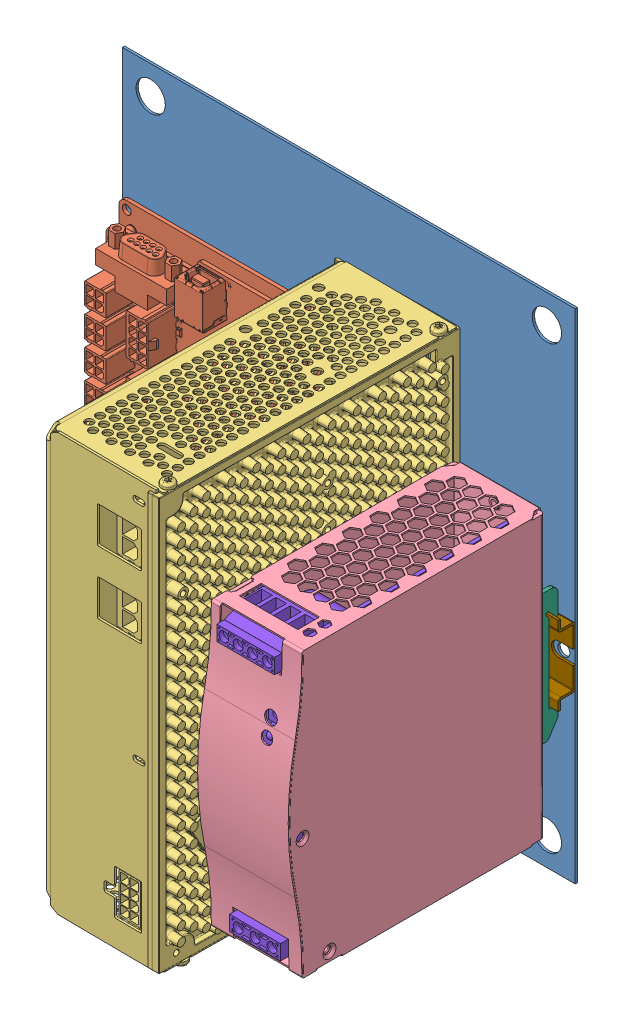
SolidWorks assembly electrical_cabinet, configuration Default. Lengths in mm.
Overall size (200 220 133.14).
13 component instances, 9 part files, 12 mates.
Components (placement in the parent):
- electrical_cabinet_plate-1: electrical_cabinet_plate [Default] at (-14.9258 10.2269 0.4282) size (200 220 1)
- sc4_hub-1: sc4_hub [Default] at (41.6255 37.6203 58.0759) x (0 -1 0) z (0 0 1) size (142.33 90.42 20.74)
- motor_power_supply-1: motor_power_supply [Default] at (-5.6586 34.4468 82.4041) x (0 1 0) z (0.008727 0 -0.999962) size (187.35 57.6 132.1)
- 24v_power_supply.step-2: 24v_power_supply.step [Default] at (97.8103 -25.1763 114.2811) x (0 0 -1) z (0 1 0) size (124.26 40 129.21)
  - a2.step-1: a2.step [Default] at origin size (113.95 40 125.2)
    - a1.step-1: a1.step [Default] at origin size (113.95 40 125.2)
      - ˋ°Ûy.step-1: ˋ°Ûy.step [Default] at (1.8 -0.5 0) size (113.95 40 125.2)
  - 掛座小.step-1: 掛座小.step [Default] at (11.5 4 0) size (11.01 31.8 94.21)
    - f.step-1: f.step [Default] at (0 52.5 0.3597) size (3 1.6 6)
    - p3.step-1: p3.step [Default] at (68.003 -1943.4948 -2522.3252) x (0 1 0) z (1 0 0) size (31.8 84.5 10)
    - p1.step-1: p1.step [Default] at (-39.4 96.9723 27) x (1 0 0) z (0 0 -1) size (8.81 16.6 54.01)
  - ¤ïÊl.step-1: ¤ïÊl.step [Default] at (-1.9005 76.5473 24.1104) x (1 0 0) z (0 0 -1) size (111.66 38.25 122)
- din_rail-1: din_rail [8961K84] at (47.0742 -12.6931 1.4282) x (0 0 -1) z (1 0 0) size (7.5 35 38)
Mates (geometry in assembly coordinates):
- Coincident1: coincident aligned: circle of electrical_cabinet_plate-1; circle of sc4_hub-1
- Concentric8: concentric aligned: cylinder of electrical_cabinet_plate-1 through (-5.1658 -83.1431 1.4282) axis (0 0 -1) radius 2.1526; cylinder of motor_power_supply-1 through (-5.1658 -83.1431 1.4282) axis (0 0 -1) radius 1.7272
- Coincident4: coincident anti-aligned: plane of electrical_cabinet_plate-1 through (-14.9258 10.2269 1.4282) normal (0 0 1); plane of motor_power_supply-1 through (29.3532 -94.1331 1.4282) normal (0 0 -1)
- Concentric10: concentric aligned: cylinder of electrical_cabinet_plate-1 through (-5.1658 76.8769 1.4282) axis (0 0 -1) radius 2.1526; cylinder of motor_power_supply-1 through (-5.1658 76.8769 1.4282) axis (0 0 -1) radius 1.7272
- Parallel6: parallel aligned: plane of electrical_cabinet_plate-1 through (-114.9258 120.2269 1.4282) normal (-1 0 0); plane of sc4_hub-1 through (-114.9298 60.7735 2.9776) normal (-1 0 0)
- Parallel7: parallel anti-aligned: plane of electrical_cabinet_plate-1 through (-14.9258 10.2269 1.4282) normal (0 0 1); plane of 24v_power_supply.step-2/a2.step-1/a1.step-1/ˋ°Ûy.step-1 through (51.5742 -4.1363 14.9282) normal (0 0 -1)
- Coincident11: coincident aligned: plane of electrical_cabinet_plate-1 through (85.0742 120.2269 1.4282) normal (1 0 0); plane of 24v_power_supply.step-2/a2.step-1/a1.step-1/ˋ°Ûy.step-1 through (85.0742 -25.1763 126.1482) normal (1 0 0)
- Coincident7: coincident anti-aligned: plane of electrical_cabinet_plate-1 through (-14.9258 10.2269 1.4282) normal (0 0 1); plane of din_rail-1 through (97.8742 -26.1931 1.4282) normal (0 0 -1)
- Coincident8: coincident aligned: plane of electrical_cabinet_plate-1 through (85.0742 120.2269 1.4282) normal (1 0 0); plane of din_rail-1 through (85.0742 4.8069 1.4282) normal (1 0 0)
- Coincident9: coincident anti-aligned: plane of 24v_power_supply.step-2/掛座小.step-1/p3.step-1 through (86.3742 3.4835 8.9282) normal (0 0 -1); plane of din_rail-1 through (97.8742 0.8069 8.9282) normal (0 0 1)
- Coincident10: coincident: plane of 24v_power_supply.step-2/掛座小.step-1/p3.step-1 through (86.3742 4.2196 7.4282) normal (0 -0.648236 0.761439); line of din_rail-1 through (85.0742 4.8069 7.9282) axis (-1 0 0)
- Width1: width: plane of din_rail-1 through (78.7242 -15.8431 8.9282) normal (0 1 0); plane of electrical_cabinet_plate-1 through (78.7242 -9.5431 8.9282) normal (0 -1 0); cylinder of din_rail-1 through (80.0742 -12.6931 1.4282) axis (0 0 -1) radius 2.65
